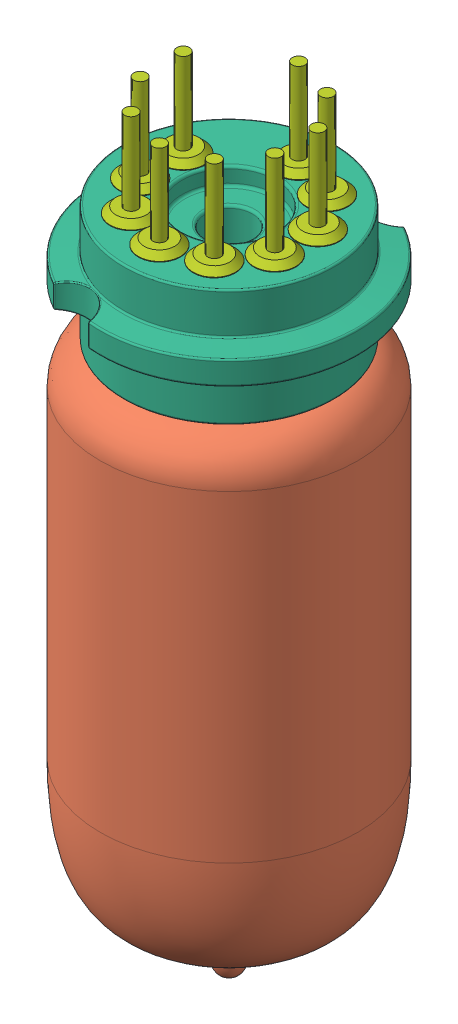
SolidWorks assembly ECC88, configuration Default. Lengths in mm.
Overall size (28.08 64.55 28.08).
17 component instances, 7 part files, 18 mates.
Components (placement in the parent):
- ecc88_pins-1: ecc88_pins [Default[As Machined]] at origin size (13.29 29 16)
- ecc88_balon-1: ecc88_balon [Default] at (0 0.3 0) x (-0.942759 0 0.333474) z (0.333474 0 0.942759) size (22 47 22)
- ecc88_insulator-1: ecc88_insulator [Default] at (0 -13 0) x (1 0 0) z (0 1 0) size (20.66 20.66 0.2)
- ecc88_insulator-2: ecc88_insulator [Default] at (0 -22.2 0) x (1 0 0) z (0 1 0) size (20.66 20.66 0.2)
- ecc88_reflector-1: ecc88_reflector [Default] at (0 -23 0) x (-1 0 0) z (0 -1 0) size (9 11.15 6.35)
- ecc88_heater-1: ecc88_heater [Default] at (0 -17.5 0) x (1 0 0) z (0 1 0) size (8.8 0.8 10)
- Noval socket-1: Noval socket [Default] at (-0.0701 3.1216 2.4528) x (-0.30103 0 0.953615) z (0.953615 0 0.30103) size (21.51 17.55 22)
  - noval ceramic body-1: noval ceramic body [Default] at (-2.3601 2.8216 -0.6716) size (21.51 10 22)
  - Noval pin-1: Noval pin [Default] at (-2.3601 43.7724 -6.6716) size (3.6 17.55 3.6)
  - Noval pin-2: Noval pin [Default] at (1.1666 43.7724 -5.5257) x (0.809017 0 0.587785) z (-0.587785 0 0.809017) size (3.6 17.55 3.6)
  - Noval pin-3: Noval pin [Default] at (3.3462 43.7724 -2.5257) x (0.309017 0 0.951057) z (-0.951057 0 0.309017) size (3.6 17.55 3.6)
  - Noval pin-4: Noval pin [Default] at (3.3462 43.7724 1.1825) x (-0.309017 0 0.951057) z (-0.951057 0 -0.309017) size (3.6 17.55 3.6)
  - Noval pin-5: Noval pin [Default] at (1.1666 43.7724 4.1825) x (-0.809017 0 0.587785) z (-0.587785 0 -0.809017) size (3.6 17.55 3.6)
  - Noval pin-6: Noval pin [Default] at (-2.3601 43.7724 5.3284) x (-1 0 0) z (0 0 -1) size (3.6 17.55 3.6)
  - Noval pin-7: Noval pin [Default] at (-5.8869 43.7724 4.1825) x (-0.809017 0 -0.587785) z (0.587785 0 -0.809017) size (3.6 17.55 3.6)
  - Noval pin-8: Noval pin [Default] at (-8.0665 43.7724 1.1825) x (-0.309017 0 -0.951057) z (0.951057 0 -0.309017) size (3.6 17.55 3.6)
  - Noval pin-9: Noval pin [Default] at (-8.0665 43.7724 -2.5257) x (0.309017 0 -0.951057) z (0.951057 0 0.309017) size (3.6 17.55 3.6)
Mates (geometry in assembly coordinates):
- Coincident1: coordinate: point of ecc88_pins-1; point of assembly
- Parallel1: parallel: plane of ecc88_pins-1 through (0 -0.01 0) normal (0 -1 0); plane of ecc88_balon-1 through (0 0.3 0) normal (0 1 0)
- Distance1: distance = 0.3 mm: plane of ecc88_pins-1 through (0 0 0) normal (0 1 0); plane of ecc88_balon-1 through (0 0.3 0) normal (0 1 0)
- Concentric1: concentric: cylinder of ecc88_pins-1 through (0 -0.01 0) axis (0 1 0) radius 5.945; cylinder of ecc88_balon-1 through (0 0.3 0) axis (0 1 0) radius 11
- InPlace1: in place: plane of ecc88_insulator-1 through (0 -13 0) normal (0 1 0); moOrthogonalPlaneRef_w of ecc88_insulator-1 through (0 -13 0) normal (0 0 -1); line of ecc88_insulator-1 through (-55 0 -13) axis (0 1 0); unknown of ecc88_insulator-1
- Coincident2: coincident: plane of ecc88_insulator-1; plane of assembly
- Coincident3: coincident: plane of ecc88_insulator-1 through (0 -13 0) normal (0 0 -1); moOrthogonalPlaneRef_w of assembly
- Coincident4: coincident: plane of ecc88_insulator-1; moOrthogonalPlaneRef_w of assembly
- InPlace2: in place: plane of ecc88_pins-1 through (0 -23 6.5) normal (0 -1 0); plane of ecc88_reflector-1 through (0 -23 0) normal (0 -1 0); plane of ecc88_pins-1 through (0 -23 6.5) normal (0 -1 0); unknown of ecc88_reflector-1; plane of ecc88_pins-1 through (0 -23 6.5) normal (0 -1 0); line of ecc88_reflector-1 through (-55 0 -23) axis (0 -1 0); plane of ecc88_pins-1 through (0 -23 6.5) normal (0 -1 0); unknown of ecc88_reflector-1
- Coincident5: coincident: plane of ecc88_pins-1; plane of ecc88_reflector-1
- Coincident6: coincident: moOrthogonalPlaneRef_w of ecc88_pins-1 through (0 -23 0) normal (0 0 -1); plane of ecc88_reflector-1
- Coincident7: coincident: moOrthogonalPlaneRef_w of ecc88_pins-1 through (0 -23 0) normal (1 0 0); plane of ecc88_reflector-1
- InPlace3: in place: plane of ecc88_heater-1 through (0 -17.5 0) normal (0 1 0); plane of ecc88_heater-1 through (0 -17.5 0) normal (0 0 -1); line of ecc88_heater-1 through (-55 0 -17.5) axis (0 1 0); unknown of ecc88_heater-1
- Coincident8: coincident: plane of ecc88_heater-1; plane of assembly
- Coincident9: coincident: plane of ecc88_heater-1 through (0 -17.5 0) normal (0 0 -1); moOrthogonalPlaneRef_w of assembly
- Coincident10: coincident: plane of ecc88_heater-1; moOrthogonalPlaneRef_w of assembly
- 同心1: concentric: circle of ecc88_balon-1; circle of Noval socket-1/noval ceramic body-1
- 重合1: coincident: plane of ecc88_balon-1 through (0 0.3 0) normal (0 1 0); plane of Noval socket-1/noval ceramic body-1 through (-2.6641 0.3 8.4395) normal (0 -1 0)
